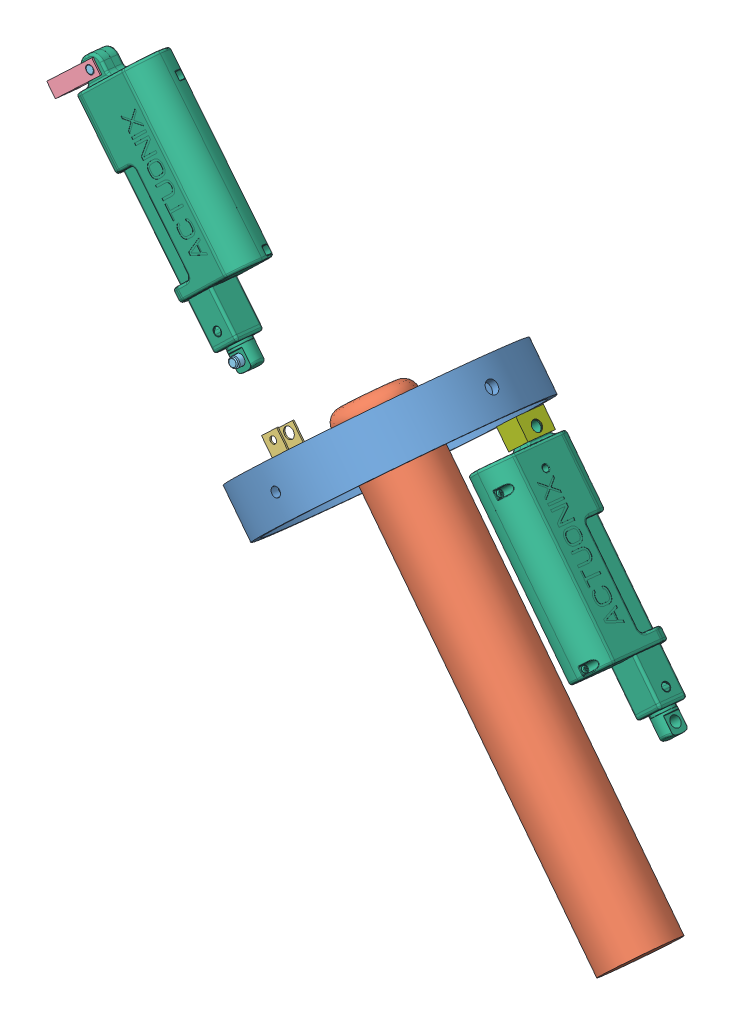
SolidWorks assembly Assembly, configuration Default. Lengths in mm.
Overall size (272.85 228.61 117.14).
11 component instances, 9 part files, 24 mates.
Components (placement in the parent):
- BodyTube-2: BodyTube [Default] at (115.4207 234.3467 -37.6347) x (0.722931 0.680008 -0.122307) z (0.03763 0.138007 0.989716) size (249.72 330.2 287.26) (hidden)
- GimbalRing-2: GimbalRing [Default] at (3.684 350.9755 -49.6492) x (-0.03763 -0.138007 -0.989716) z (0.722931 0.680008 -0.122307) size (101.6 19.05 101.6)
- EngineCasing-2: EngineCasing [Default] at (115.3951 234.3734 -37.6375) x (0.03763 0.138007 0.989716) z (-0.722931 -0.680008 0.122307) size (29 186.69 29)
- Actuator Fastener Gimbal-2: Actuator Fastener Gimbal [Default] at (-44.532 334.892 -45.0601) x (-0.03763 -0.138007 -0.989716) z (0.722931 0.680008 -0.122307) size (7.62 9.14 7.62)
- Actuator Fastener BodyTube-3: Actuator Fastener BodyTube [Default] at (-144.4001 419.3551 -52.0665) x (-0.03763 -0.138007 -0.989716) z (0.689894 -0.720099 0.074181) size (9.65 22.66 5.84)
- Actuator Fastoning pin-1: Actuator Fastoning pin [Default] at (-61.4239 360.4528 -43.3101) x (0.999288 -0.00261 -0.03763) z (0.03763 0.138007 0.989716) size (4.83 4.83 11.76)
- p16_50mm_in(Actuator)-1: p16_50mm_in(Actuator) [Default] at (-134.1948 418.4253 -53.8384) x (-0.712452 -0.690783 0.123411) z (0.700711 -0.709769 0.072329) size (36.18 20.01 105.9)
- Actuator Fastoning pin-2: Actuator Fastoning pin [Default] at (-129.7134 429.4369 -51.4119) x (0.999288 -0.00261 -0.03763) z (0.03763 0.138007 0.989716) size (4.83 4.83 11.76)
- Actuator 2 Fastoner to Gimbal Ring-1: Actuator 2 Fastoner to Gimbal Ring [Default] at (1.2867 343.8226 -96.7894) x (-0.722931 -0.680008 0.122307) z (0.03763 0.138007 0.989716) size (9.65 8.38 12.19)
- p16_50mm_in(Actuator)-3: p16_50mm_in(Actuator) [Default] at (9.7164 337.4072 -108.3196) x (-0.03763 -0.138007 -0.989716) z (0.689894 -0.720099 0.074181) size (36.18 20.01 105.9)
- Actuator 1 Fastener Engine Casing-1: Actuator 1 Fastener Engine Casing [Default] at (77.8375 252.2198 -55.1487) x (-0.710781 -0.692472 0.123583) z (0.702406 -0.708122 0.072035) size (7.62 9.91 7.62)
Mates (geometry in assembly coordinates):
- Gimbal Hole Allignment: concentric: cylinder of BodyTube-2 through (-0.4722 366.5712 12.4939) axis (0.03763 0.138007 0.989716) radius 2.5527; cylinder of GimbalRing-2 through (-0.9501 364.8185 -0.0755) axis (-0.03763 -0.138007 -0.989716) radius 1.905
- BT Hole Allignment: coincident: plane of BodyTube-2 through (115.4207 234.3467 -37.6347) normal (0.03763 0.138007 0.989716); plane of GimbalRing-2 through (3.684 350.9755 -49.6492) normal (-0.03763 -0.138007 -0.989716)
- Engine Hole Allignment: concentric: cylinder of GimbalRing-2 through (-25.8403 336.2442 -46.4726) axis (-0.722931 -0.680008 0.122307) radius 2.5527; cylinder of EngineCasing-2 through (7.1362 367.2627 -52.0516) axis (0.722931 0.680008 -0.122307) radius 1.905
- GR to Casing Allignment: coincident: plane of GimbalRing-2 through (3.684 350.9755 -49.6492) normal (0.722931 0.680008 -0.122307); plane of EngineCasing-2 through (115.3951 234.3734 -37.6375) normal (-0.722931 -0.680008 0.122307)
- keeping gimbal zero: parallel: plane of BodyTube-2 through (-112.3824 472.1235 -62.1293) normal (-0.689894 0.720099 -0.074181); plane of GimbalRing-2 through (-9.4585 364.6934 -51.0624) normal (-0.689894 0.720099 -0.074181)
- keeping engine casing zero: parallel: plane of GimbalRing-2 through (-9.4585 364.6934 -51.0624) normal (-0.689894 0.720099 -0.074181); plane of EngineCasing-2 through (-13.4013 368.8087 -51.4863) normal (-0.689894 0.720099 -0.074181)
- Actuator 1 Fastening Allignment: coincident: plane of GimbalRing-2 through (-9.4585 364.6934 -51.0624) normal (-0.689894 0.720099 -0.074181); plane of Actuator Fastener Gimbal-2 through (-37.3159 338.8862 -42.5027) normal (0.689894 -0.720099 0.074181)
- Parallel3: parallel: plane of EngineCasing-2 through (115.3951 234.3734 -37.6375) normal (-0.722931 -0.680008 0.122307); plane of Actuator Fastener Gimbal-2 through (-44.532 334.892 -45.0601) normal (0.722931 0.680008 -0.122307)
- Distance2: distance = 46.355 mm: plane of Actuator Fastener Gimbal-2 through (-44.532 334.892 -45.0601) normal (0.722931 0.680008 -0.122307); plane of EngineCasing-2 through (115.3951 234.3734 -37.6375) normal (-0.722931 -0.680008 0.122307)
- Coincident4: coincident: line of BodyTube-2 through (77.3376 433.2453 -63.9214) axis (-0.722931 -0.680008 0.122307); plane of Actuator Fastener Gimbal-2 through (-44.5511 334.8219 -45.5628) normal (-0.03763 -0.138007 -0.989716)
- Concentric4: concentric: circle of BodyTube-2; circle of Actuator Fastener BodyTube-3
- Tangent1: tangent: circle of BodyTube-2; plane of Actuator Fastener BodyTube-3 through (-144.4001 419.3551 -52.0665) normal (-0.689894 0.720099 -0.074181)
- Parallel6: parallel: plane of Actuator Fastener Gimbal-2 through (-44.5511 334.8219 -45.5628) normal (-0.03763 -0.138007 -0.989716); plane of assembly through (-0.0212 -0.0777 -0.5572) normal (-0.03763 -0.138007 -0.989716)
- Concentric8: concentric: cylinder of Actuator Fastoning pin-1 through (-61.7584 359.2259 -52.1087) axis (0.03763 0.138007 0.989716) radius 2.032; cylinder of p16_50mm_in(Actuator)-1 through (-61.7873 359.1199 -52.8686) axis (0.03763 0.138007 0.989716) radius 2.125
- Coincident12: coincident: plane of Actuator Fastener Gimbal-2 through (-37.6027 337.8346 -50.0443) normal (-0.03763 -0.138007 -0.989716); plane of Actuator Fastoning pin-1 through (-61.7584 359.2259 -52.1087) normal (0.03763 0.138007 0.989716)
- Concentric9: concentric: cylinder of Actuator Fastener BodyTube-3 through (-129.6846 429.5422 -50.6567) axis (-0.03763 -0.138007 -0.989716) radius 2.159; cylinder of p16_50mm_in(Actuator)-1 through (-130.0178 428.3205 -59.4186) axis (0.03763 0.138007 0.989716) radius 2.125
- Distance4: distance = 0.1651 mm: plane of p16_50mm_in(Actuator)-1 through (-122.6016 427.8706 -59.6378) normal (-0.03763 -0.138007 -0.989716); plane of Actuator Fastener BodyTube-3 through (-125.9889 428.0942 -59.7071) normal (0.03763 0.138007 0.989716)
- Concentric10: concentric: cylinder of p16_50mm_in(Actuator)-1 through (-130.0178 428.3205 -59.4186) axis (0.03763 0.138007 0.989716) radius 2.125; cylinder of Actuator Fastoning pin-2 through (-130.0479 428.21 -60.2105) axis (0.03763 0.138007 0.989716) radius 2.032
- Coincident13: coincident: plane of Actuator Fastener BodyTube-3 through (-142.2636 412.7207 -57.5862) normal (-0.03763 -0.138007 -0.989716); plane of Actuator Fastoning pin-2 through (-130.0479 428.21 -60.2105) normal (0.03763 0.138007 0.989716)
- Parallel11: parallel: line of Actuator 2 Fastoner to Gimbal Ring-1 through (6.7618 348.1953 -105.2618) axis (0.03763 0.138007 0.989716); plane of p16_50mm_in(Actuator)-3 through (16.9457 344.2073 -109.5427) normal (0.722931 0.680008 -0.122307)
- Concentric20: concentric: circle of Actuator 2 Fastoner to Gimbal Ring-1; cylinder of p16_50mm_in(Actuator)-3 through (9.8987 344.8168 -98.7506) axis (-0.722931 -0.680008 0.122307) radius 2.125
- Coincident24: coincident: plane of Actuator 2 Fastoner to Gimbal Ring-1 through (3.558 345.959 -97.1737) normal (-0.722931 -0.680008 0.122307); plane of p16_50mm_in(Actuator)-3 through (9.7164 337.4072 -108.3196) normal (0.722931 0.680008 -0.122307)
- Coincident25: coincident: plane of Actuator 2 Fastoner to Gimbal Ring-1 through (1.231 343.6184 -98.254) normal (0.03763 0.138007 0.989716); plane of p16_50mm_in(Actuator)-3 through (10.1115 338.8563 -97.9276) normal (0.03763 0.138007 0.989716)
- Coincident36: coincident: plane of Actuator 1 Fastener Engine Casing-1 through (80.5136 249.5219 -54.8742) normal (-0.702406 0.708122 -0.072035); plane of assembly through (-87.1626 87.8719 -8.939) normal (0.702406 -0.708122 0.072035)
